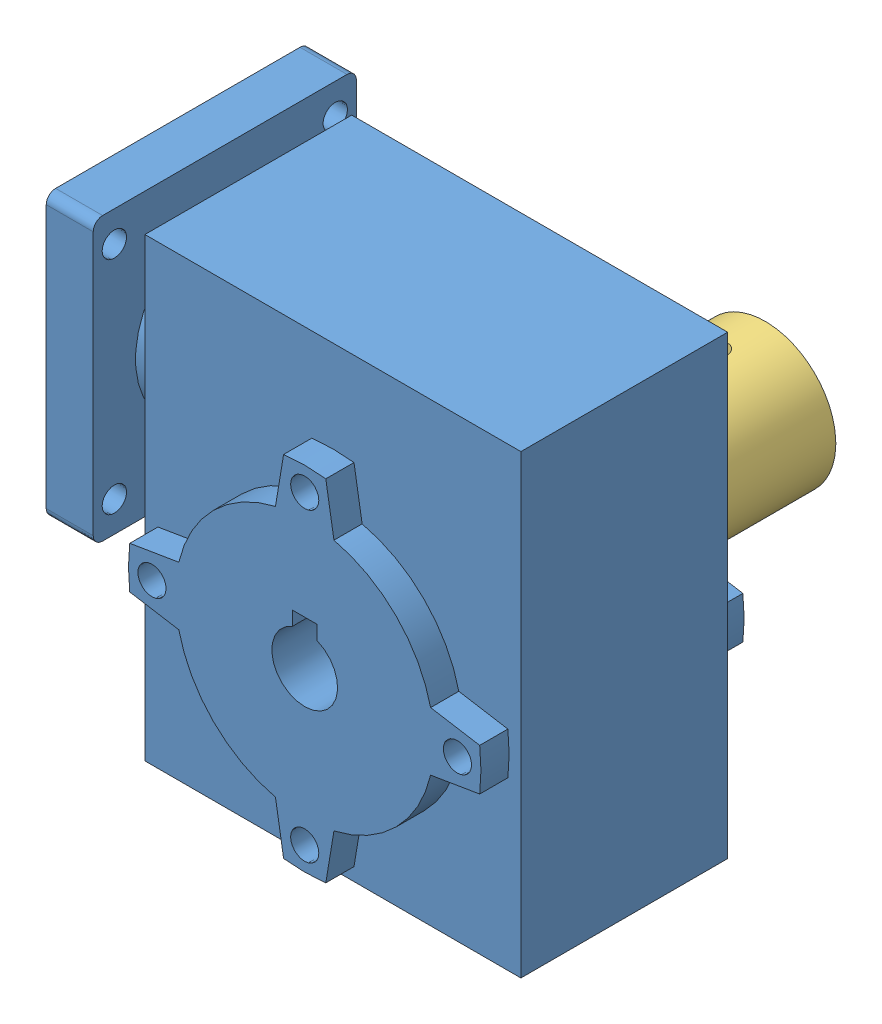
SolidWorks assembly mecanum3, configuration 默认. Lengths in mm.
Overall size (95 100 98).
4 component instances, 3 part files, 2 mates.
Components (placement in the parent):
- 电机整套-1: 电机整套 [默认] at (189.3936 41.1641 -46.7546) size (95 100 76)
  - 减速器-1: 减速器 [默认] at (54.7667 -0.0575 136) size (95 100 56)
  - 14mm输出轴-1: 14mm输出轴 [默认] at (76.5366 -30.9692 88) size (14 14 30)
- 联轴器-1: 联轴器 [默认] at (254.3448 30.1333 19.2454) size (30 30 42)
Mates (geometry in assembly coordinates):
- 重合1: coincident: plane of 电机整套-1/减速器-1 through (254.3448 27.7598 61.2454) normal (0 0 -1); plane of 联轴器-1 through (254.3448 27.7598 61.2454) normal (0 0 1)
- 同心1: concentric: cylinder of 电机整套-1/14mm输出轴-1 through (254.3448 27.7598 71.2454) axis (0 0 -1) radius 7; cylinder of 联轴器-1 through (254.3448 27.7598 41.2454) axis (0 0 1) radius 7
